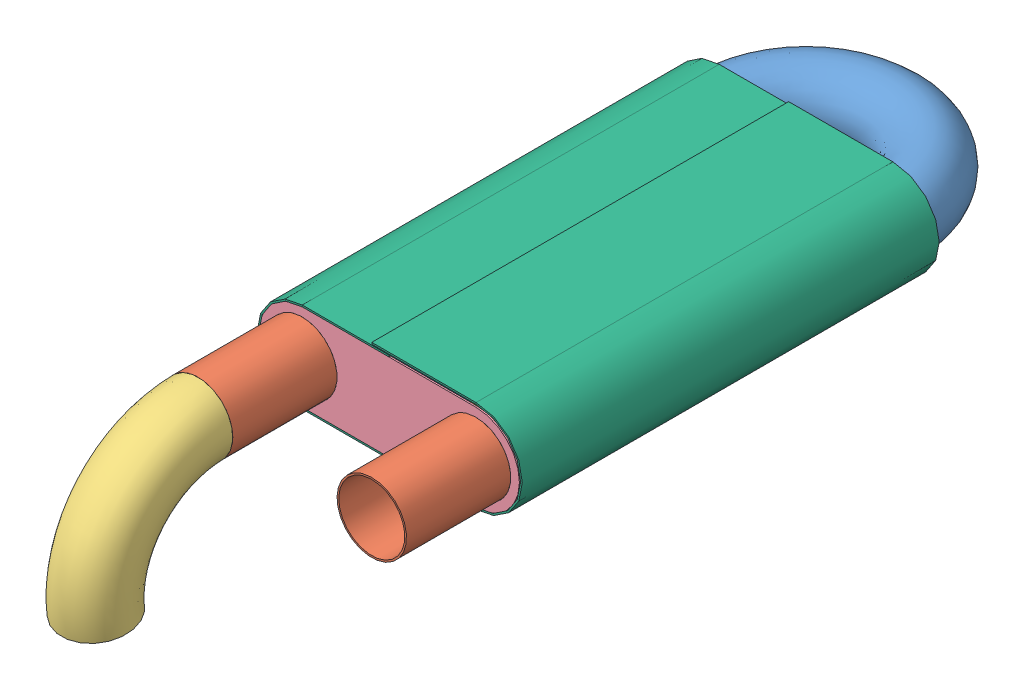
SolidWorks assembly muffler, configuration Default. Lengths in mm.
Overall size (197.58 126.62 583.37).
10 component instances, 7 part files, 22 mates.
Components (placement in the parent):
- u bend pipe-1: u bend pipe [Default] at (-77.9471 20.1933 27.4126) size (177.8 50.8 88.9)
- tippart2-1: tippart2 [Default] at (-77.9471 20.1933 332.2126) size (50.8 50.8 76.2)
- tippart2-2: tippart2 [Default] at (49.0529 20.1933 408.4126) x (-0.397535 0.917587 0) z (0 0 -1) size (50.8 50.8 76.2)
- tippart1-1: tippart1 [Default] at (-77.9471 -65.3599 483.0194) x (0 0.136058 -0.990701) z (0 -0.990701 -0.136058) size (114.41 50.8 100.71)
- inner braket-1: inner braket [Default] at (-14.4471 20.1933 28.5708) x (1 0 0) z (0 0 -1) size (190.5 63.5 1.16)
- inner braket-2: inner braket [Default] at (-14.4471 20.1933 331.0543) size (190.5 63.5 1.16)
- inner plate-2: inner plate [Default] at (-14.4471 -11.5567 331.0543) size (1.26 63.5 302.48)
- outtercansheetmetal-1: outtercansheetmetal [Default] at (-77.9471 -11.5567 27.4126) size (193.83 67.72 304.8)
- Baffel tube-1: Baffel tube [Default] at (-77.9471 20.1933 28.5743) x (0.98892 0.14845 0) z (0 0 1) size (53.29 53.29 302.48)
- Baffel tube-2: Baffel tube [Default] at (49.0529 20.1933 28.5743) x (-0.748332 0.663324 0) z (0 0 1) size (53.29 53.29 302.48)
Mates (geometry in assembly coordinates):
- Coincident9: coincident aligned: cylinder of tippart2-1 through (-77.9471 20.1933 408.4126) axis (0 0 -1) radius 25.4; circle of inner braket-1
- Coincident10: coincident aligned: circle of tippart2-1; circle of inner braket-2
- Concentric5: concentric anti-aligned: cylinder of tippart2-1 through (-77.9471 20.1933 408.4126) axis (0 0 -1) radius 25.4; cylinder of Baffel tube-1 through (-77.9471 20.1933 -163.599) axis (0 0 1) radius 26.6446
- Concentric6: concentric anti-aligned: cylinder of inner braket-2 through (49.0529 20.1933 332.2126) axis (0 0 -1) radius 25.4; cylinder of Baffel tube-2 through (49.0529 20.1933 -163.599) axis (0 0 1) radius 25.4
- Coincident32: coincident anti-aligned: plane of inner braket-2 through (-77.9471 20.1933 331.0543) normal (0 0 -1); plane of Baffel tube-2 through (49.0529 20.1933 331.0543) normal (0 0 1)
- Concentric7: concentric anti-aligned: cylinder of tippart2-2 through (49.0529 20.1933 332.2126) axis (0 0 1) radius 25.4; cylinder of inner braket-2 through (49.0529 20.1933 332.2126) axis (0 0 -1) radius 25.4
- Coincident33: coincident aligned: plane of inner braket-1 through (-77.9471 20.1933 27.4126) normal (0 0 -1); plane of outtercansheetmetal-1 through (49.0529 21.0823 27.4126) normal (0 0 -1)
- Coincident34: coincident anti-aligned: plane of inner braket-2 through (-77.9471 51.9433 332.2126) normal (0 1 0); plane of outtercansheetmetal-1 through (-77.9471 51.9433 332.2126) normal (0 -1 0)
- Coincident35: coincident anti-aligned: plane of inner braket-1 through (-77.9471 -11.5567 27.4126) normal (0 -1 0); plane of outtercansheetmetal-1 through (-77.9471 -11.5567 332.2126) normal (0 1 0)
- Coincident36: coincident anti-aligned: plane of tippart2-2 through (49.0529 20.1933 332.2126) normal (0 0 -1); plane of inner braket-2 through (-77.9471 20.1933 332.2126) normal (0 0 1)
- Concentric9: concentric anti-aligned: circle of u bend pipe-1; cylinder of Baffel tube-2 through (49.0529 20.1933 -163.599) axis (0 0 1) radius 25.4
- Concentric10: concentric aligned: circle of u bend pipe-1; cylinder of Baffel tube-1 through (-77.9471 20.1933 -163.599) axis (0 0 1) radius 25.4
- Concentric11: concentric anti-aligned: circle of u bend pipe-1; cylinder of Baffel tube-2 through (49.0529 20.1933 -163.599) axis (0 0 1) radius 25.4
- Coincident37: coincident anti-aligned: plane of u bend pipe-1 through (-77.9471 20.1933 27.4126) normal (0 0 1); plane of inner braket-1 through (-77.9471 20.1933 27.4126) normal (0 0 -1)
- Coincident38: coincident aligned: plane of inner braket-2 through (-77.9471 20.1933 332.2126) normal (0 0 1); plane of outtercansheetmetal-1 through (-77.9471 -11.5567 332.2126) normal (0 0 1)
- Coincident39: coincident anti-aligned: plane of inner braket-2 through (-77.9471 20.1933 331.0543) normal (0 0 -1); plane of Baffel tube-1 through (-77.9471 20.1933 331.0543) normal (0 0 1)
- Coincident40: coincident anti-aligned: plane of inner braket-2 through (-77.9471 20.1933 331.0543) normal (0 0 -1); plane of inner plate-2 through (-13.8184 51.9433 331.0543) normal (0 0 1)
- Coincident41: coincident aligned: plane of inner braket-2 through (-14.4471 20.1933 331.0543) normal (1 0 0); plane of inner plate-2 through (-14.4471 -11.5567 331.0543) normal (1 0 0)
- Coincident42: coincident aligned: plane of inner braket-2 through (-77.9471 51.9433 332.2126) normal (0 1 0); plane of inner plate-2 through (-13.8184 51.9433 28.5743) normal (0 1 0)
- Coincident43: coincident anti-aligned: cylinder of tippart2-1 through (-77.9471 20.1933 408.4126) axis (0 0 -1) radius 24.1554; circle of tippart1-1
- Coincident44: coincident anti-aligned: plane of tippart2-1 through (-77.9471 20.1933 408.4126) normal (0 0 1); plane of tippart1-1 through (-77.9471 20.1933 408.4126) normal (0 0 -1)
- Perpendicular1: perpendicular: plane of tippart1-1; plane of outtercansheetmetal-1 through (-77.9471 53.1625 332.2126) normal (0 1 0)
